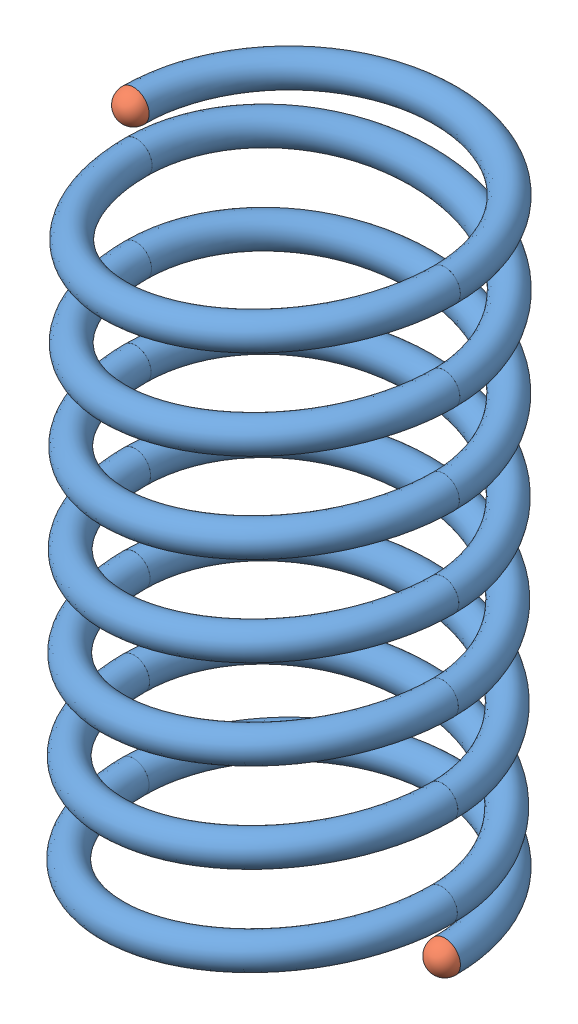
SolidWorks assembly spring, configuration Default. Lengths in mm.
Overall size (111.29 198.04 110).
18 component instances, 3 part files, 49 mates.
Components (placement in the parent):
- one section-1: one section [Default] at (0 13.1296 0) size (110 10 55)
- one section-2: one section [Default] at (-0.4823 20.0575 0) x (0.990354 0.138557 0) z (0 0 -1) size (110 10 55)
- one section-3: one section [Default] at (-0.4019 34.4653 0) x (0.988747 -0.149599 0) z (0 0 1) size (110 10 55)
- one section-5: one section [Default] at (-0.3215 48.8731 0) x (0.990354 0.138557 0) z (0 0 -1) size (110 10 55)
- one section-6: one section [Default] at (-0.2411 63.2809 0) x (0.988747 -0.149599 0) z (0 0 1) size (110 10 55)
- one section-8: one section [Default] at (-0.1608 77.6887 0) x (0.990354 0.138557 0) z (0 0 -1) size (110 10 55)
- one section-9: one section [Default] at (-0.0804 92.0965 0) x (0.988747 -0.149599 0) z (0 0 1) size (110 10 55)
- one section-10: one section [Default] at (0 106.5043 0) x (0.990354 0.138557 0) z (0 0 -1) size (110 10 55)
- one section-11: one section [Default] at (0.0804 120.9121 0) x (0.988747 -0.149599 0) z (0 0 1) size (110 10 55)
- one section-12: one section [Default] at (0.1608 135.32 0) x (0.990354 0.138557 0) z (0 0 -1) size (110 10 55)
- one section-13: one section [Default] at (0.2411 149.7278 0) x (0.988747 -0.149599 0) z (0 0 1) size (110 10 55)
- one section-14: one section [Default] at (0.3215 164.1356 0) x (0.990354 0.138557 0) z (0 0 -1) size (110 10 55)
- one section-15: one section [Default] at (0.4019 178.5434 0) x (0.988747 -0.149599 0) z (0 0 1) size (110 10 55)
- one section-16: one section [Default] at (0.4823 192.9512 0) x (0.990354 0.138557 0) z (0 0 -1) size (110 10 55)
- one section-17: one section [Default] at (0 199.8791 0) size (110 10 55)
- end-1: end [Default] at (-50 199.8791 0) size (10 10 5)
- end-2: end [Default] at (50 13.1296 0) size (10 10 5)
- pin-1: pin [Default] at origin size (10 10 10) (hidden)
Mates (geometry in assembly coordinates):
- Coincident11: coincident anti-aligned: plane of one section-1 through (-50 13.1296 0) normal (0 0 1); plane of one section-2 through (-50 13.1296 0) normal (0 0 -1)
- Coincident21: coincident anti-aligned: line of one section-1 through (-50 13.1296 0) axis (0 0 1); line of one section-2 through (-50 13.1296 0) axis (0 0 -1)
- Coincident31: coincident anti-aligned: plane of one section-2 through (49.0354 26.9854 0) normal (0 0 -1); plane of one section-3 through (49.0354 26.9854 0) normal (0 0 1)
- Coincident41: coincident anti-aligned: line of one section-2 through (49.0354 26.9854 0) axis (0 0 -1); line of one section-3 through (49.0354 26.9854 0) axis (0 0 1)
- Coincident71: coincident anti-aligned: plane of one section-3 through (-49.8392 41.9452 0) normal (0 0 1); plane of one section-5 through (-49.8392 41.9452 0) normal (0 0 -1)
- Coincident81: coincident anti-aligned: line of one section-3 through (-49.8392 41.9452 0) axis (0 0 1); line of one section-5 through (-49.8392 41.9452 0) axis (0 0 -1)
- Coincident91: coincident anti-aligned: plane of one section-5 through (49.1962 55.801 0) normal (0 0 -1); plane of one section-6 through (49.1962 55.801 0) normal (0 0 1)
- Coincident101: coincident anti-aligned: line of one section-5 through (49.1962 55.801 0) axis (0 0 -1); line of one section-6 through (49.1962 55.801 0) axis (0 0 1)
- Coincident131: coincident anti-aligned: plane of one section-6 through (-49.6785 70.7609 0) normal (0 0 1); plane of one section-8 through (-49.6785 70.7609 0) normal (0 0 -1)
- Coincident141: coincident anti-aligned: line of one section-6 through (-49.6785 70.7609 0) axis (0 0 1); line of one section-8 through (-49.6785 70.7609 0) axis (0 0 -1)
- Coincident151: coincident anti-aligned: plane of one section-8 through (49.357 84.6166 0) normal (0 0 -1); plane of one section-9 through (49.357 84.6166 0) normal (0 0 1)
- Coincident161: coincident anti-aligned: line of one section-8 through (49.357 84.6166 0) axis (0 0 -1); line of one section-9 through (49.357 84.6166 0) axis (0 0 1)
- Coincident171: coincident anti-aligned: plane of one section-9 through (-49.5177 99.5765 0) normal (0 0 1); plane of one section-10 through (-49.5177 99.5765 0) normal (0 0 -1)
- Coincident181: coincident anti-aligned: line of one section-9 through (-49.5177 99.5765 0) axis (0 0 1); line of one section-10 through (-49.5177 99.5765 0) axis (0 0 -1)
- Coincident191: coincident anti-aligned: plane of one section-10 through (49.5177 113.4322 0) normal (0 0 -1); plane of one section-11 through (49.5177 113.4322 0) normal (0 0 1)
- Coincident201: coincident anti-aligned: line of one section-10 through (49.5177 113.4322 0) axis (0 0 -1); line of one section-11 through (49.5177 113.4322 0) axis (0 0 1)
- Coincident211: coincident anti-aligned: plane of one section-11 through (-49.357 128.3921 0) normal (0 0 1); plane of one section-12 through (-49.357 128.3921 0) normal (0 0 -1)
- Coincident221: coincident anti-aligned: line of one section-11 through (-49.357 128.3921 0) axis (0 0 1); line of one section-12 through (-49.357 128.3921 0) axis (0 0 -1)
- Coincident231: coincident anti-aligned: plane of one section-12 through (49.6785 142.2478 0) normal (0 0 -1); plane of one section-13 through (49.6785 142.2478 0) normal (0 0 1)
- Coincident241: coincident anti-aligned: line of one section-12 through (49.6785 142.2478 0) axis (0 0 -1); line of one section-13 through (49.6785 142.2478 0) axis (0 0 1)
- Coincident251: coincident anti-aligned: plane of one section-13 through (-49.1962 157.2077 0) normal (0 0 1); plane of one section-14 through (-49.1962 157.2077 0) normal (0 0 -1)
- Coincident261: coincident anti-aligned: line of one section-13 through (-49.1962 157.2077 0) axis (0 0 1); line of one section-14 through (-49.1962 157.2077 0) axis (0 0 -1)
- Coincident271: coincident anti-aligned: plane of one section-14 through (49.8392 171.0634 0) normal (0 0 -1); plane of one section-15 through (49.8392 171.0634 0) normal (0 0 1)
- Coincident281: coincident anti-aligned: line of one section-14 through (49.8392 171.0634 0) axis (0 0 -1); line of one section-15 through (49.8392 171.0634 0) axis (0 0 1)
- Coincident291: coincident anti-aligned: plane of one section-15 through (-49.0354 186.0233 0) normal (0 0 1); plane of one section-16 through (-49.0354 186.0233 0) normal (0 0 -1)
- Coincident301: coincident anti-aligned: line of one section-15 through (-49.0354 186.0233 0) axis (0 0 1); line of one section-16 through (-49.0354 186.0233 0) axis (0 0 -1)
- Coincident311: coincident anti-aligned: plane of one section-16 through (50 199.8791 0) normal (0 0 -1); plane of one section-17 through (50 199.8791 0) normal (0 0 1)
- Coincident321: coincident anti-aligned: line of one section-16 through (50 199.8791 0) axis (0 0 -1); line of one section-17 through (50 199.8791 0) axis (0 0 1)
- Parallel1: parallel aligned: plane of one section-15; plane of one section-13
- Parallel2: parallel aligned: plane of one section-15; plane of one section-11
- Parallel3: parallel aligned: plane of one section-15; plane of one section-9
- Parallel4: parallel aligned: plane of one section-15; plane of one section-6
- Parallel5: parallel aligned: plane of one section-15; plane of one section-3
- Parallel6: parallel aligned: plane of one section-16; plane of one section-14
- Parallel7: parallel aligned: plane of one section-16; plane of one section-12
- Parallel8: parallel aligned: plane of one section-16; plane of one section-10
- Parallel9: parallel aligned: plane of one section-16; plane of one section-8
- Parallel10: parallel aligned: plane of one section-16; plane of one section-5
- Parallel11: parallel aligned: plane of one section-16; plane of one section-2
- Parallel12: parallel aligned: plane of one section-17 through (0 199.8791 0) normal (0 1 0); plane of one section-1 through (0 13.1296 0) normal (0 1 0)
- Coincident33: coincident aligned: plane of one section-1 through (0 13.1296 0) normal (1 0 0); plane of one section-17 through (0 199.8791 0) normal (1 0 0)
- Coincident34: coincident anti-aligned: plane of one section-17 through (-50 199.8791 0) normal (0 0 1); plane of end-1 through (-50 199.8791 0) normal (0 0 -1)
- Coincident35: coincident aligned: circle of one section-17; circle of end-1
- Coincident36: coincident anti-aligned: circle of one section-1; circle of end-2
- Coincident37: coincident: plane of one section-1 through (0 13.1296 0) normal (1 0 0); plane of assembly through (0 0 0) normal (1 0 0)
- Coincident38: coincident: plane of one section-1 through (0 13.1296 0) normal (0 0 1); plane of assembly through (0 0 0) normal (0 0 1)
- Coincident39: coincident: plane of pin-1 through (0 0 0) normal (1 0 0); plane of assembly through (0 0 0) normal (1 0 0)
- Coincident40: coincident: plane of pin-1 through (0 0 0) normal (0 0 1); plane of assembly through (0 0 0) normal (0 0 1)
- Coincident41: coincident: plane of pin-1 through (0 0 0) normal (0 1 0); plane of assembly through (0 0 0) normal (0 1 0)
